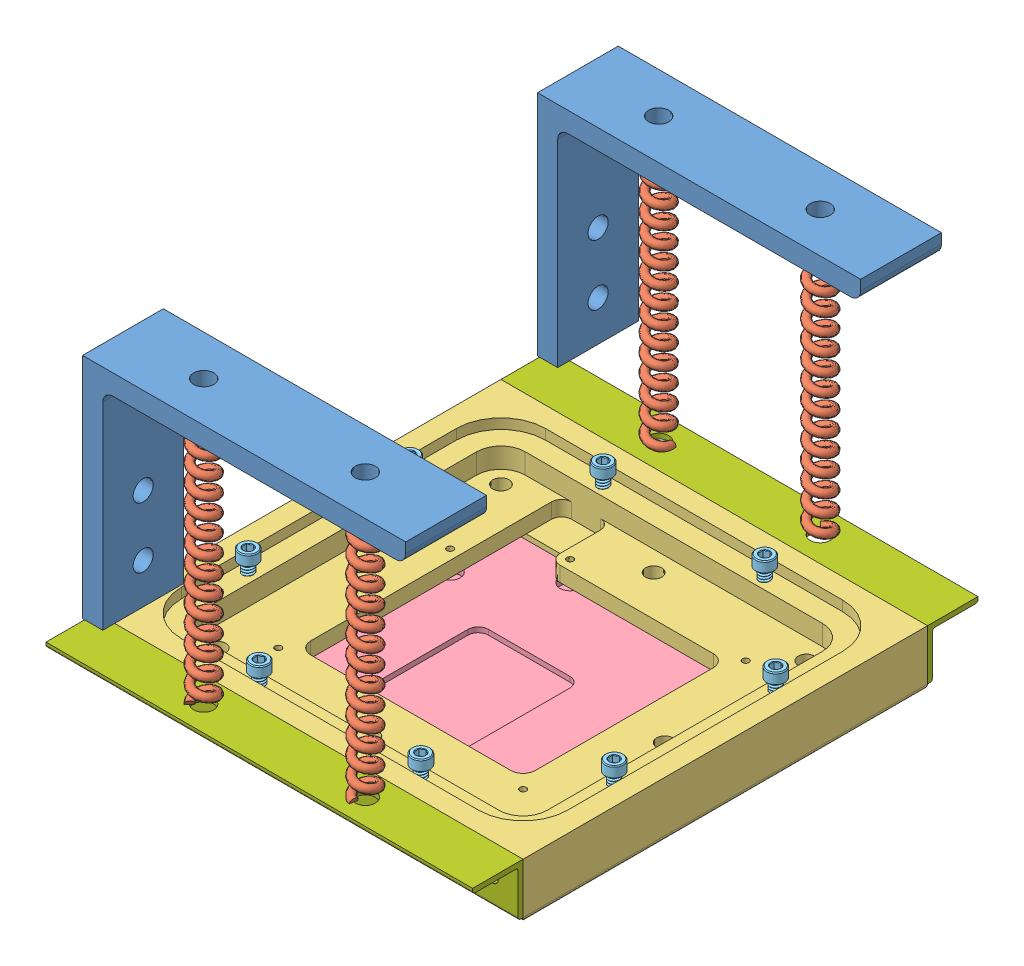
SolidWorks assembly SensorAssembly, configuration Default. Lengths in mm.
Overall size (134.11 107.62 168.43).
24 component instances, 8 part files, 28 mates.
Components (placement in the parent):
- Sensor Mount Bracket-1: Sensor Mount Bracket [8982K286] at (7.5304 4.2584 -62.5585) x (0 1 0) z (0 0 -1) size (71.68 101.6 25.4)
- Sensor Mount Bracket-2: Sensor Mount Bracket [8982K286] at (7.5304 4.2584 80.4689) x (0 1 0) z (0 0 -1) size (71.68 101.6 25.4)
- Rudimentary Spring-1: Rudimentary Spring [Default] at (32.9304 -46.2161 -62.5585) x (-0.500882 0 0.865515) z (-0.865515 0 -0.500882) size (9.16 86.7 9.16)
- Rudimentary Spring-2: Rudimentary Spring [Default] at (83.7304 -46.2161 -62.5585) x (0.992471 0 0.122483) z (-0.122483 0 0.992471) size (9.16 86.7 9.16)
- Rudimentary Spring-3: Rudimentary Spring [Default] at (32.9304 -46.2161 80.4689) x (-0.055094 0 -0.998481) z (0.998481 0 -0.055094) size (9.16 86.7 9.16)
- Rudimentary Spring-4: Rudimentary Spring [Default] at (83.7304 36.0084 80.4689) x (0.816732 0 -0.577017) z (-0.577017 0 -0.816732) size (9.16 86.7 9.16)
- NDE Sensor Mount Assembly-2: NDE Sensor Mount Assembly [Default] at (58.3304 -65.2661 8.9552) size (134.11 22.72 127.15)
  - CaseBody-1: CaseBody [Default] at origin size (134.11 17.46 127.15)
  - WearPlateAndMount-1: WearPlateAndMount [Default] at (0 3.175 0) size (108.71 3.17 101.75)
  - Cover Plate-1: Cover Plate [Default] at (0 15.875 0) size (121.41 3.17 114.45) (hidden)
  - 97334A146_NYLON SOCKET HEAD CAP SCREW-1: 97334A146_NYLON SOCKET HEAD CAP SCREW [97334A146] at (-57.531 9.525 -25.4) x (1 0 0) z (0 -1 0) size (5.74 5.74 13.88)
  - 97334A146_NYLON SOCKET HEAD CAP SCREW-2: 97334A146_NYLON SOCKET HEAD CAP SCREW [97334A146] at (-57.531 9.525 25.4) x (1 0 0) z (0 -1 0) size (5.74 5.74 13.88)
  - 97334A146_NYLON SOCKET HEAD CAP SCREW-3: 97334A146_NYLON SOCKET HEAD CAP SCREW [97334A146] at (-25.4 9.525 54.0512) x (1 0 0) z (0 -1 0) size (5.74 5.74 13.88)
  - 97334A146_NYLON SOCKET HEAD CAP SCREW-4: 97334A146_NYLON SOCKET HEAD CAP SCREW [97334A146] at (-25.4 9.525 -54.0512) x (1 0 0) z (0 -1 0) size (5.74 5.74 13.88)
  - 97334A146_NYLON SOCKET HEAD CAP SCREW-5: 97334A146_NYLON SOCKET HEAD CAP SCREW [97334A146] at (25.4 9.525 -54.0512) x (1 0 0) z (0 -1 0) size (5.74 5.74 13.88)
  - 97334A146_NYLON SOCKET HEAD CAP SCREW-6: 97334A146_NYLON SOCKET HEAD CAP SCREW [97334A146] at (25.4 9.525 54.0512) x (1 0 0) z (0 -1 0) size (5.74 5.74 13.88)
  - 97334A146_NYLON SOCKET HEAD CAP SCREW-7: 97334A146_NYLON SOCKET HEAD CAP SCREW [97334A146] at (57.531 9.525 -25.4) x (1 0 0) z (0 -1 0) size (5.74 5.74 13.88)
  - 97334A146_NYLON SOCKET HEAD CAP SCREW-8: 97334A146_NYLON SOCKET HEAD CAP SCREW [97334A146] at (57.531 9.525 25.4) x (1 0 0) z (0 -1 0) size (5.74 5.74 13.88)
- 97164A111_TAPEARED HEAT-SET INSERTS FOR PLASTIC -1: 97164A111_TAPEARED HEAT-SET INSERTS FOR PLASTIC  [97164A111] at (-0.7881 -54.1536 68.7214) x (1 0 0) z (0 -1 0) size (5.6 7.12 5.61)
- 97164A111_TAPEARED HEAT-SET INSERTS FOR PLASTIC -2: 97164A111_TAPEARED HEAT-SET INSERTS FOR PLASTIC  [97164A111] at (117.4489 -54.1536 68.7214) x (1 0 0) z (0 -1 0) size (5.6 7.12 5.61)
- 97164A111_TAPEARED HEAT-SET INSERTS FOR PLASTIC -3: 97164A111_TAPEARED HEAT-SET INSERTS FOR PLASTIC  [97164A111] at (-0.7881 -54.1536 -50.811) x (-0.923728 -0.383049 0) z (0.383049 -0.923728 0) size (5.6 7.12 5.61)
- 97164A111_TAPEARED HEAT-SET INSERTS FOR PLASTIC -4: 97164A111_TAPEARED HEAT-SET INSERTS FOR PLASTIC  [97164A111] at (117.4489 -54.1536 -50.811) x (-0.923728 -0.383049 0) z (0.383049 -0.923728 0) size (5.6 7.12 5.61)
- 8982K511_MULTIPURPOSE 6061 ALUMINUM 90 DEGREE ANGLE (1)-1: 8982K511_MULTIPURPOSE 6061 ALUMINUM 90 DEGREE ANGLE (1) [8982K511] at (58.3304 -54.1536 -54.621) x (0 1 0) z (-1 0 0) size (15.88 15.88 134.11)
- 8982K511_MULTIPURPOSE 6061 ALUMINUM 90 DEGREE ANGLE (1)-4: 8982K511_MULTIPURPOSE 6061 ALUMINUM 90 DEGREE ANGLE (1) [8982K511] at (58.3304 -54.1536 72.5314) x (0 1 0) z (1 0 0) size (15.88 15.88 134.11)
Mates (geometry in assembly coordinates):
- Coincident18: coincident anti-aligned: plane of Revised NDE Sensor Mount-1/CaseBody-1 through (-0.7881 -54.1536 66.1814) normal (0 0 1); plane of 97164A111_TAPEARED HEAT-SET INSERTS FOR PLASTIC -1 through (1.2947 -54.1536 66.1814) normal (0 0 -1)
- Concentric7: concentric aligned: circle of Revised NDE Sensor Mount-1/CaseBody-1; circle of 97164A111_TAPEARED HEAT-SET INSERTS FOR PLASTIC -1
- Coincident19: coincident anti-aligned: plane of Revised NDE Sensor Mount-1/CaseBody-1 through (-0.7881 -54.1536 -48.271) normal (0 0 -1); plane of 97164A111_TAPEARED HEAT-SET INSERTS FOR PLASTIC -3 through (-2.712 -54.9514 -48.271) normal (0 0 1)
- Concentric8: concentric aligned: cylinder of Revised NDE Sensor Mount-1/CaseBody-1 through (-0.7881 -54.1536 -48.271) axis (0 0 -1) radius 2.3495; circle of 97164A111_TAPEARED HEAT-SET INSERTS FOR PLASTIC -3
- Coincident20: coincident anti-aligned: plane of Revised NDE Sensor Mount-1/CaseBody-1 through (117.4489 -54.1536 -48.271) normal (0 0 -1); plane of 97164A111_TAPEARED HEAT-SET INSERTS FOR PLASTIC -4 through (115.525 -54.9514 -48.271) normal (0 0 1)
- Concentric9: concentric aligned: cylinder of Revised NDE Sensor Mount-1/CaseBody-1 through (117.4489 -54.1536 -48.271) axis (0 0 -1) radius 2.3495; circle of 97164A111_TAPEARED HEAT-SET INSERTS FOR PLASTIC -4
- Coincident21: coincident anti-aligned: plane of Revised NDE Sensor Mount-1/CaseBody-1 through (117.4489 -54.1536 66.1814) normal (0 0 1); plane of 97164A111_TAPEARED HEAT-SET INSERTS FOR PLASTIC -2 through (119.5317 -54.1536 66.1814) normal (0 0 -1)
- Concentric10: concentric aligned: cylinder of Revised NDE Sensor Mount-1/CaseBody-1 through (117.4489 -54.1536 66.1814) axis (0 0 1) radius 2.3495; circle of 97164A111_TAPEARED HEAT-SET INSERTS FOR PLASTIC -2
- Concentric18: concentric anti-aligned: cylinder of Sensor Mount Bracket-2 through (83.7304 -33.8426 80.4689) axis (0 1 0) radius 3.175; cylinder of Rudimentary Spring-4 through (83.7304 38.4576 80.4689) axis (0 -1 0) radius 2.019
- Concentric20: concentric aligned: cylinder of Sensor Mount Bracket-2 through (32.9304 -33.8426 80.4689) axis (0 1 0) radius 3.175; cylinder of Rudimentary Spring-3 through (32.9304 -48.6653 80.4689) axis (0 1 0) radius 2.019
- Coincident28: coincident anti-aligned: plane of NDE Sensor Mount Assembly-2/CaseBody-1 through (58.3304 -49.3911 -54.621) normal (0 0 -1); plane of 8982K511_MULTIPURPOSE 6061 ALUMINUM 90 DEGREE ANGLE (1)-1 through (-8.7256 -62.0911 -54.621) normal (0 0 1)
- Coincident29: coincident aligned: plane of NDE Sensor Mount Assembly-2/CaseBody-1 through (-8.7256 -49.3911 8.9552) normal (-1 0 0); plane of 8982K511_MULTIPURPOSE 6061 ALUMINUM 90 DEGREE ANGLE (1)-1 through (-8.7256 -47.0098 -69.7022) normal (-1 0 0)
- Coincident30: coincident aligned: plane of NDE Sensor Mount Assembly-2/CaseBody-1 through (58.3304 -46.2161 8.9552) normal (0 1 0); plane of 8982K511_MULTIPURPOSE 6061 ALUMINUM 90 DEGREE ANGLE (1)-1 through (-8.7256 -46.2161 -54.621) normal (0 1 0)
- Coincident31: coincident anti-aligned: plane of NDE Sensor Mount Assembly-2/CaseBody-1 through (58.3304 -49.3911 72.5314) normal (0 0 1); plane of 8982K511_MULTIPURPOSE 6061 ALUMINUM 90 DEGREE ANGLE (1)-4 through (125.3864 -62.0911 72.5314) normal (0 0 -1)
- Coincident32: coincident aligned: plane of NDE Sensor Mount Assembly-2/CaseBody-1 through (-8.7256 -49.3911 8.9552) normal (-1 0 0); plane of 8982K511_MULTIPURPOSE 6061 ALUMINUM 90 DEGREE ANGLE (1)-4 through (-8.7256 -47.0098 87.6127) normal (-1 0 0)
- Coincident33: coincident aligned: plane of NDE Sensor Mount Assembly-2/CaseBody-1 through (58.3304 -46.2161 8.9552) normal (0 1 0); plane of 8982K511_MULTIPURPOSE 6061 ALUMINUM 90 DEGREE ANGLE (1)-4 through (125.3864 -46.2161 72.5314) normal (0 1 0)
- Coincident38: coincident anti-aligned: plane of Rudimentary Spring-2 through (77.6844 -43.8312 -46.9318) normal (0 -1 0); plane of 8982K511_MULTIPURPOSE 6061 ALUMINUM 90 DEGREE ANGLE (1)-1 through (-8.7256 -46.2161 -54.621) normal (0 1 0)
- Concentric21: concentric aligned: cylinder of Rudimentary Spring-2 through (83.1519 -46.2804 -53.6136) axis (0 1 0) radius 2.019; cylinder of 8982K511_MULTIPURPOSE 6061 ALUMINUM 90 DEGREE ANGLE (1)-1 through (83.7304 -62.0911 -62.5585) axis (0 1 0) radius 3.175
- Concentric22: concentric anti-aligned: cylinder of Rudimentary Spring-4 through (83.7304 38.4576 80.4689) axis (0 -1 0) radius 2.019; cylinder of 8982K511_MULTIPURPOSE 6061 ALUMINUM 90 DEGREE ANGLE (1)-4 through (83.7304 -62.0911 80.4689) axis (0 1 0) radius 3.175
- Coincident40: coincident anti-aligned: plane of Sensor Mount Bracket-2 through (105.9554 36.0084 67.7689) normal (0 -1 0); plane of Rudimentary Spring-3 through (43.4253 36.0084 84.5048) normal (0 1 0)
- Coincident41: coincident anti-aligned: plane of Sensor Mount Bracket-2 through (105.9554 36.0084 67.7689) normal (0 -1 0); plane of Rudimentary Spring-4 through (75.7541 36.0084 77.1647) normal (0 1 0)
- Concentric23: concentric aligned: cylinder of Rudimentary Spring-3 through (32.9304 -48.6653 80.4689) axis (0 1 0) radius 2.019; cylinder of 8982K511_MULTIPURPOSE 6061 ALUMINUM 90 DEGREE ANGLE (1)-4 through (32.9304 -62.0911 80.4689) axis (0 1 0) radius 3.175
- Coincident42: coincident anti-aligned: plane of Rudimentary Spring-3 through (40.4744 -46.2161 84.6676) normal (0 -1 0); plane of 8982K511_MULTIPURPOSE 6061 ALUMINUM 90 DEGREE ANGLE (1)-4 through (125.3864 -46.2161 72.5314) normal (0 1 0)
- Coincident43: coincident aligned: plane of Sensor Mount Bracket-1 through (7.5304 -33.8416 -48.5095) normal (-1 0 0); plane of Sensor Mount Bracket-2 through (7.5304 -33.8416 67.7689) normal (-1 0 0)
- Coincident44: coincident aligned: plane of Sensor Mount Bracket-1 through (7.5304 42.3584 -48.5095) normal (0 1 0); plane of Sensor Mount Bracket-2 through (7.5304 42.3584 67.7689) normal (0 1 0)
- Coincident45: coincident anti-aligned: plane of Sensor Mount Bracket-1 through (105.9554 36.0084 -48.5095) normal (0 -1 0); plane of Rudimentary Spring-1 through (26.3612 36.0084 -44.9351) normal (0 1 0)
- Concentric24: concentric aligned: cylinder of Sensor Mount Bracket-1 through (32.9304 -33.8426 -35.8095) axis (0 1 0) radius 3.175; cylinder of Rudimentary Spring-1 through (32.9304 -48.6653 -35.8095) axis (0 1 0) radius 2.019
- Concentric25: concentric aligned: cylinder of Sensor Mount Bracket-1 through (83.7304 -33.8426 -62.5585) axis (0 1 0) radius 3.175; cylinder of Rudimentary Spring-2 through (83.7304 -48.6653 -62.5585) axis (0 1 0) radius 2.019
